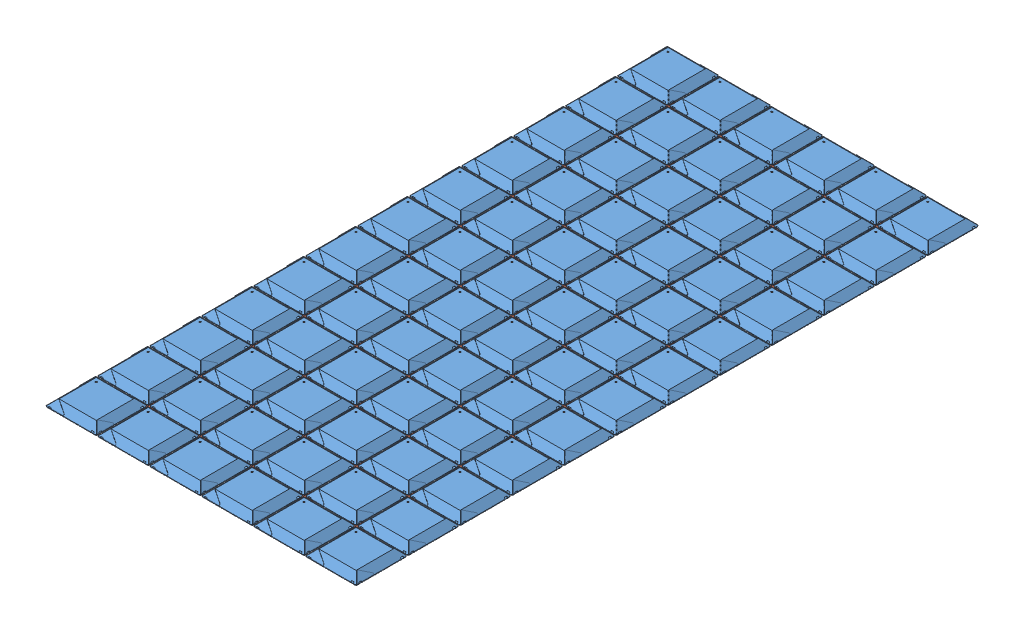
SolidWorks assembly window6x12, configuration Default. Lengths in mm.
Overall size (1214.93 43.24 2434.13).
127 component instances, 2 part files, 1 mates.
Components (placement in the parent):
- ecstatic-diffuser-sheet-1: ecstatic-diffuser-sheet [Default] at (70.6237 101.6767 147.5762) size (198.93 27.79 198.93)
- ecstatic-vertex4-1: ecstatic-vertex4 [Default] at (411.2878 97.7397 270.4125) size (232.82 27.79 232.82)
- ecstatic-diffuser-sheet-2: ecstatic-diffuser-sheet [Default] at (70.6237 101.6767 350.7762) size (198.93 27.79 198.93)
- ecstatic-diffuser-sheet-3: ecstatic-diffuser-sheet [Default] at (70.6237 101.6767 553.9762) size (198.93 27.79 198.93)
- ecstatic-diffuser-sheet-4: ecstatic-diffuser-sheet [Default] at (70.6237 101.6767 757.1762) size (198.93 27.79 198.93)
- ecstatic-diffuser-sheet-5: ecstatic-diffuser-sheet [Default] at (70.6237 101.6767 960.3762) size (198.93 27.79 198.93)
- ecstatic-diffuser-sheet-6: ecstatic-diffuser-sheet [Default] at (70.6237 101.6767 1163.5762) size (198.93 27.79 198.93)
- ecstatic-diffuser-sheet-7: ecstatic-diffuser-sheet [Default] at (70.6237 101.6767 1366.7762) size (198.93 27.79 198.93)
- ecstatic-diffuser-sheet-8: ecstatic-diffuser-sheet [Default] at (70.6237 101.6767 1569.9762) size (198.93 27.79 198.93)
- ecstatic-diffuser-sheet-9: ecstatic-diffuser-sheet [Default] at (70.6237 101.6767 1773.1762) size (198.93 27.79 198.93)
- ecstatic-diffuser-sheet-10: ecstatic-diffuser-sheet [Default] at (70.6237 101.6767 1976.3762) size (198.93 27.79 198.93)
- ecstatic-diffuser-sheet-11: ecstatic-diffuser-sheet [Default] at (70.6237 101.6767 2179.5762) size (198.93 27.79 198.93)
- ecstatic-diffuser-sheet-12: ecstatic-diffuser-sheet [Default] at (70.6237 101.6767 2382.7762) size (198.93 27.79 198.93)
- ecstatic-diffuser-sheet-13: ecstatic-diffuser-sheet [Default] at (273.8237 101.6767 147.5762) size (198.93 27.79 198.93)
- ecstatic-diffuser-sheet-14: ecstatic-diffuser-sheet [Default] at (273.8237 101.6767 350.7762) size (198.93 27.79 198.93)
- ecstatic-diffuser-sheet-15: ecstatic-diffuser-sheet [Default] at (273.8237 101.6767 553.9762) size (198.93 27.79 198.93)
- ecstatic-diffuser-sheet-16: ecstatic-diffuser-sheet [Default] at (273.8237 101.6767 757.1762) size (198.93 27.79 198.93)
- ecstatic-diffuser-sheet-17: ecstatic-diffuser-sheet [Default] at (273.8237 101.6767 960.3762) size (198.93 27.79 198.93)
- ecstatic-diffuser-sheet-18: ecstatic-diffuser-sheet [Default] at (273.8237 101.6767 1163.5762) size (198.93 27.79 198.93)
- ecstatic-diffuser-sheet-19: ecstatic-diffuser-sheet [Default] at (273.8237 101.6767 1366.7762) size (198.93 27.79 198.93)
- ecstatic-diffuser-sheet-20: ecstatic-diffuser-sheet [Default] at (273.8237 101.6767 1569.9762) size (198.93 27.79 198.93)
- ecstatic-diffuser-sheet-21: ecstatic-diffuser-sheet [Default] at (273.8237 101.6767 1773.1762) size (198.93 27.79 198.93)
- ecstatic-diffuser-sheet-22: ecstatic-diffuser-sheet [Default] at (273.8237 101.6767 1976.3762) size (198.93 27.79 198.93)
- ecstatic-diffuser-sheet-23: ecstatic-diffuser-sheet [Default] at (273.8237 101.6767 2179.5762) size (198.93 27.79 198.93)
- ecstatic-diffuser-sheet-24: ecstatic-diffuser-sheet [Default] at (273.8237 101.6767 2382.7762) size (198.93 27.79 198.93)
- ecstatic-diffuser-sheet-25: ecstatic-diffuser-sheet [Default] at (477.0237 101.6767 147.5762) size (198.93 27.79 198.93)
- ecstatic-diffuser-sheet-26: ecstatic-diffuser-sheet [Default] at (477.0237 101.6767 350.7762) size (198.93 27.79 198.93)
- ecstatic-diffuser-sheet-27: ecstatic-diffuser-sheet [Default] at (477.0237 101.6767 553.9762) size (198.93 27.79 198.93)
- ecstatic-diffuser-sheet-28: ecstatic-diffuser-sheet [Default] at (477.0237 101.6767 757.1762) size (198.93 27.79 198.93)
- ecstatic-diffuser-sheet-29: ecstatic-diffuser-sheet [Default] at (477.0237 101.6767 960.3762) size (198.93 27.79 198.93)
- ecstatic-diffuser-sheet-30: ecstatic-diffuser-sheet [Default] at (477.0237 101.6767 1163.5762) size (198.93 27.79 198.93)
- ecstatic-diffuser-sheet-31: ecstatic-diffuser-sheet [Default] at (477.0237 101.6767 1366.7762) size (198.93 27.79 198.93)
- ecstatic-diffuser-sheet-32: ecstatic-diffuser-sheet [Default] at (477.0237 101.6767 1569.9762) size (198.93 27.79 198.93)
- ecstatic-diffuser-sheet-33: ecstatic-diffuser-sheet [Default] at (477.0237 101.6767 1773.1762) size (198.93 27.79 198.93)
- ecstatic-diffuser-sheet-34: ecstatic-diffuser-sheet [Default] at (477.0237 101.6767 1976.3762) size (198.93 27.79 198.93)
- ecstatic-diffuser-sheet-35: ecstatic-diffuser-sheet [Default] at (477.0237 101.6767 2179.5762) size (198.93 27.79 198.93)
- ecstatic-diffuser-sheet-36: ecstatic-diffuser-sheet [Default] at (477.0237 101.6767 2382.7762) size (198.93 27.79 198.93)
- ecstatic-diffuser-sheet-37: ecstatic-diffuser-sheet [Default] at (680.2237 101.6767 147.5762) size (198.93 27.79 198.93)
- ecstatic-diffuser-sheet-38: ecstatic-diffuser-sheet [Default] at (680.2237 101.6767 350.7762) size (198.93 27.79 198.93)
- ecstatic-diffuser-sheet-39: ecstatic-diffuser-sheet [Default] at (680.2237 101.6767 553.9762) size (198.93 27.79 198.93)
- ecstatic-diffuser-sheet-40: ecstatic-diffuser-sheet [Default] at (680.2237 101.6767 757.1762) size (198.93 27.79 198.93)
- ecstatic-diffuser-sheet-41: ecstatic-diffuser-sheet [Default] at (680.2237 101.6767 960.3762) size (198.93 27.79 198.93)
- ecstatic-diffuser-sheet-42: ecstatic-diffuser-sheet [Default] at (680.2237 101.6767 1163.5762) size (198.93 27.79 198.93)
- ecstatic-diffuser-sheet-43: ecstatic-diffuser-sheet [Default] at (680.2237 101.6767 1366.7762) size (198.93 27.79 198.93)
- ecstatic-diffuser-sheet-44: ecstatic-diffuser-sheet [Default] at (680.2237 101.6767 1569.9762) size (198.93 27.79 198.93)
- ecstatic-diffuser-sheet-45: ecstatic-diffuser-sheet [Default] at (680.2237 101.6767 1773.1762) size (198.93 27.79 198.93)
- ecstatic-diffuser-sheet-46: ecstatic-diffuser-sheet [Default] at (680.2237 101.6767 1976.3762) size (198.93 27.79 198.93)
- ecstatic-diffuser-sheet-47: ecstatic-diffuser-sheet [Default] at (680.2237 101.6767 2179.5762) size (198.93 27.79 198.93)
- ecstatic-diffuser-sheet-48: ecstatic-diffuser-sheet [Default] at (680.2237 101.6767 2382.7762) size (198.93 27.79 198.93)
- ecstatic-diffuser-sheet-49: ecstatic-diffuser-sheet [Default] at (883.4237 101.6767 147.5762) size (198.93 27.79 198.93)
- ecstatic-diffuser-sheet-50: ecstatic-diffuser-sheet [Default] at (883.4237 101.6767 350.7762) size (198.93 27.79 198.93)
- ecstatic-diffuser-sheet-51: ecstatic-diffuser-sheet [Default] at (883.4237 101.6767 553.9762) size (198.93 27.79 198.93)
- ecstatic-diffuser-sheet-52: ecstatic-diffuser-sheet [Default] at (883.4237 101.6767 757.1762) size (198.93 27.79 198.93)
- ecstatic-diffuser-sheet-53: ecstatic-diffuser-sheet [Default] at (883.4237 101.6767 960.3762) size (198.93 27.79 198.93)
- ecstatic-diffuser-sheet-54: ecstatic-diffuser-sheet [Default] at (883.4237 101.6767 1163.5762) size (198.93 27.79 198.93)
- ecstatic-diffuser-sheet-55: ecstatic-diffuser-sheet [Default] at (883.4237 101.6767 1366.7762) size (198.93 27.79 198.93)
- ecstatic-diffuser-sheet-56: ecstatic-diffuser-sheet [Default] at (883.4237 101.6767 1569.9762) size (198.93 27.79 198.93)
- ecstatic-diffuser-sheet-57: ecstatic-diffuser-sheet [Default] at (883.4237 101.6767 1773.1762) size (198.93 27.79 198.93)
- ecstatic-diffuser-sheet-58: ecstatic-diffuser-sheet [Default] at (883.4237 101.6767 1976.3762) size (198.93 27.79 198.93)
- ecstatic-diffuser-sheet-59: ecstatic-diffuser-sheet [Default] at (883.4237 101.6767 2179.5762) size (198.93 27.79 198.93)
- ecstatic-diffuser-sheet-60: ecstatic-diffuser-sheet [Default] at (883.4237 101.6767 2382.7762) size (198.93 27.79 198.93)
- ecstatic-diffuser-sheet-61: ecstatic-diffuser-sheet [Default] at (1086.6237 101.6767 147.5762) size (198.93 27.79 198.93)
- ecstatic-diffuser-sheet-62: ecstatic-diffuser-sheet [Default] at (1086.6237 101.6767 350.7762) size (198.93 27.79 198.93)
- ecstatic-diffuser-sheet-63: ecstatic-diffuser-sheet [Default] at (1086.6237 101.6767 553.9762) size (198.93 27.79 198.93)
- ecstatic-diffuser-sheet-64: ecstatic-diffuser-sheet [Default] at (1086.6237 101.6767 757.1762) size (198.93 27.79 198.93)
- ecstatic-diffuser-sheet-65: ecstatic-diffuser-sheet [Default] at (1086.6237 101.6767 960.3762) size (198.93 27.79 198.93)
- ecstatic-diffuser-sheet-66: ecstatic-diffuser-sheet [Default] at (1086.6237 101.6767 1163.5762) size (198.93 27.79 198.93)
- ecstatic-diffuser-sheet-67: ecstatic-diffuser-sheet [Default] at (1086.6237 101.6767 1366.7762) size (198.93 27.79 198.93)
- ecstatic-diffuser-sheet-68: ecstatic-diffuser-sheet [Default] at (1086.6237 101.6767 1569.9762) size (198.93 27.79 198.93)
- ecstatic-diffuser-sheet-69: ecstatic-diffuser-sheet [Default] at (1086.6237 101.6767 1773.1762) size (198.93 27.79 198.93)
- ecstatic-diffuser-sheet-70: ecstatic-diffuser-sheet [Default] at (1086.6237 101.6767 1976.3762) size (198.93 27.79 198.93)
- ecstatic-diffuser-sheet-71: ecstatic-diffuser-sheet [Default] at (1086.6237 101.6767 2179.5762) size (198.93 27.79 198.93)
- ecstatic-diffuser-sheet-72: ecstatic-diffuser-sheet [Default] at (1086.6237 101.6767 2382.7762) size (198.93 27.79 198.93)
- ecstatic-vertex4-2: ecstatic-vertex4 [Default] at (411.2878 97.7397 473.6125) size (232.82 27.79 232.82)
- ecstatic-vertex4-3: ecstatic-vertex4 [Default] at (411.2878 97.7397 676.8125) size (232.82 27.79 232.82)
- ecstatic-vertex4-4: ecstatic-vertex4 [Default] at (411.2878 97.7397 880.0125) size (232.82 27.79 232.82)
- ecstatic-vertex4-5: ecstatic-vertex4 [Default] at (411.2878 97.7397 1083.2125) size (232.82 27.79 232.82)
- ecstatic-vertex4-6: ecstatic-vertex4 [Default] at (411.2878 97.7397 1286.4125) size (232.82 27.79 232.82)
- ecstatic-vertex4-7: ecstatic-vertex4 [Default] at (411.2878 97.7397 1489.6125) size (232.82 27.79 232.82)
- ecstatic-vertex4-8: ecstatic-vertex4 [Default] at (411.2878 97.7397 1692.8125) size (232.82 27.79 232.82)
- ecstatic-vertex4-9: ecstatic-vertex4 [Default] at (411.2878 97.7397 1896.0125) size (232.82 27.79 232.82)
- ecstatic-vertex4-10: ecstatic-vertex4 [Default] at (411.2878 97.7397 2099.2125) size (232.82 27.79 232.82)
- ecstatic-vertex4-11: ecstatic-vertex4 [Default] at (411.2878 97.7397 2302.4125) size (232.82 27.79 232.82)
- ecstatic-vertex4-12: ecstatic-vertex4 [Default] at (614.4878 97.7397 270.4125) size (232.82 27.79 232.82)
- ecstatic-vertex4-13: ecstatic-vertex4 [Default] at (614.4878 97.7397 473.6125) size (232.82 27.79 232.82)
- ecstatic-vertex4-14: ecstatic-vertex4 [Default] at (614.4878 97.7397 676.8125) size (232.82 27.79 232.82)
- ecstatic-vertex4-15: ecstatic-vertex4 [Default] at (614.4878 97.7397 880.0125) size (232.82 27.79 232.82)
- ecstatic-vertex4-16: ecstatic-vertex4 [Default] at (614.4878 97.7397 1083.2125) size (232.82 27.79 232.82)
- ecstatic-vertex4-17: ecstatic-vertex4 [Default] at (614.4878 97.7397 1286.4125) size (232.82 27.79 232.82)
- ecstatic-vertex4-18: ecstatic-vertex4 [Default] at (614.4878 97.7397 1489.6125) size (232.82 27.79 232.82)
- ecstatic-vertex4-19: ecstatic-vertex4 [Default] at (614.4878 97.7397 1692.8125) size (232.82 27.79 232.82)
- ecstatic-vertex4-20: ecstatic-vertex4 [Default] at (614.4878 97.7397 1896.0125) size (232.82 27.79 232.82)
- ecstatic-vertex4-21: ecstatic-vertex4 [Default] at (614.4878 97.7397 2099.2125) size (232.82 27.79 232.82)
- ecstatic-vertex4-22: ecstatic-vertex4 [Default] at (614.4878 97.7397 2302.4125) size (232.82 27.79 232.82)
- ecstatic-vertex4-23: ecstatic-vertex4 [Default] at (817.6878 97.7397 270.4125) size (232.82 27.79 232.82)
- ecstatic-vertex4-24: ecstatic-vertex4 [Default] at (817.6878 97.7397 473.6125) size (232.82 27.79 232.82)
- ecstatic-vertex4-25: ecstatic-vertex4 [Default] at (817.6878 97.7397 676.8125) size (232.82 27.79 232.82)
- ecstatic-vertex4-26: ecstatic-vertex4 [Default] at (817.6878 97.7397 880.0125) size (232.82 27.79 232.82)
- ecstatic-vertex4-27: ecstatic-vertex4 [Default] at (817.6878 97.7397 1083.2125) size (232.82 27.79 232.82)
- ecstatic-vertex4-28: ecstatic-vertex4 [Default] at (817.6878 97.7397 1286.4125) size (232.82 27.79 232.82)
- ecstatic-vertex4-29: ecstatic-vertex4 [Default] at (817.6878 97.7397 1489.6125) size (232.82 27.79 232.82)
- ecstatic-vertex4-30: ecstatic-vertex4 [Default] at (817.6878 97.7397 1692.8125) size (232.82 27.79 232.82)
- ecstatic-vertex4-31: ecstatic-vertex4 [Default] at (817.6878 97.7397 1896.0125) size (232.82 27.79 232.82)
- ecstatic-vertex4-32: ecstatic-vertex4 [Default] at (817.6878 97.7397 2099.2125) size (232.82 27.79 232.82)
- ecstatic-vertex4-33: ecstatic-vertex4 [Default] at (817.6878 97.7397 2302.4125) size (232.82 27.79 232.82)
- ecstatic-vertex4-34: ecstatic-vertex4 [Default] at (1020.8878 97.7397 270.4125) size (232.82 27.79 232.82)
- ecstatic-vertex4-35: ecstatic-vertex4 [Default] at (1020.8878 97.7397 473.6125) size (232.82 27.79 232.82)
- ecstatic-vertex4-36: ecstatic-vertex4 [Default] at (1020.8878 97.7397 676.8125) size (232.82 27.79 232.82)
- ecstatic-vertex4-37: ecstatic-vertex4 [Default] at (1020.8878 97.7397 880.0125) size (232.82 27.79 232.82)
- ecstatic-vertex4-38: ecstatic-vertex4 [Default] at (1020.8878 97.7397 1083.2125) size (232.82 27.79 232.82)
- ecstatic-vertex4-39: ecstatic-vertex4 [Default] at (1020.8878 97.7397 1286.4125) size (232.82 27.79 232.82)
- ecstatic-vertex4-40: ecstatic-vertex4 [Default] at (1020.8878 97.7397 1489.6125) size (232.82 27.79 232.82)
- ecstatic-vertex4-41: ecstatic-vertex4 [Default] at (1020.8878 97.7397 1692.8125) size (232.82 27.79 232.82)
- ecstatic-vertex4-42: ecstatic-vertex4 [Default] at (1020.8878 97.7397 1896.0125) size (232.82 27.79 232.82)
- ecstatic-vertex4-43: ecstatic-vertex4 [Default] at (1020.8878 97.7397 2099.2125) size (232.82 27.79 232.82)
- ecstatic-vertex4-44: ecstatic-vertex4 [Default] at (1020.8878 97.7397 2302.4125) size (232.82 27.79 232.82)
- ecstatic-vertex4-45: ecstatic-vertex4 [Default] at (1224.0878 97.7397 270.4125) size (232.82 27.79 232.82)
- ecstatic-vertex4-46: ecstatic-vertex4 [Default] at (1224.0878 97.7397 473.6125) size (232.82 27.79 232.82)
- ecstatic-vertex4-47: ecstatic-vertex4 [Default] at (1224.0878 97.7397 676.8125) size (232.82 27.79 232.82)
- ecstatic-vertex4-48: ecstatic-vertex4 [Default] at (1224.0878 97.7397 880.0125) size (232.82 27.79 232.82)
- ecstatic-vertex4-49: ecstatic-vertex4 [Default] at (1224.0878 97.7397 1083.2125) size (232.82 27.79 232.82)
- ecstatic-vertex4-50: ecstatic-vertex4 [Default] at (1224.0878 97.7397 1286.4125) size (232.82 27.79 232.82)
- ecstatic-vertex4-51: ecstatic-vertex4 [Default] at (1224.0878 97.7397 1489.6125) size (232.82 27.79 232.82)
- ecstatic-vertex4-52: ecstatic-vertex4 [Default] at (1224.0878 97.7397 1692.8125) size (232.82 27.79 232.82)
- ecstatic-vertex4-53: ecstatic-vertex4 [Default] at (1224.0878 97.7397 1896.0125) size (232.82 27.79 232.82)
- ecstatic-vertex4-54: ecstatic-vertex4 [Default] at (1224.0878 97.7397 2099.2125) size (232.82 27.79 232.82)
- ecstatic-vertex4-55: ecstatic-vertex4 [Default] at (1224.0878 97.7397 2302.4125) size (232.82 27.79 232.82)
Mates (geometry in assembly coordinates):
- Coincident3: coincident aligned: circle of ecstatic-diffuser-sheet-1; circle of ecstatic-vertex4-1
